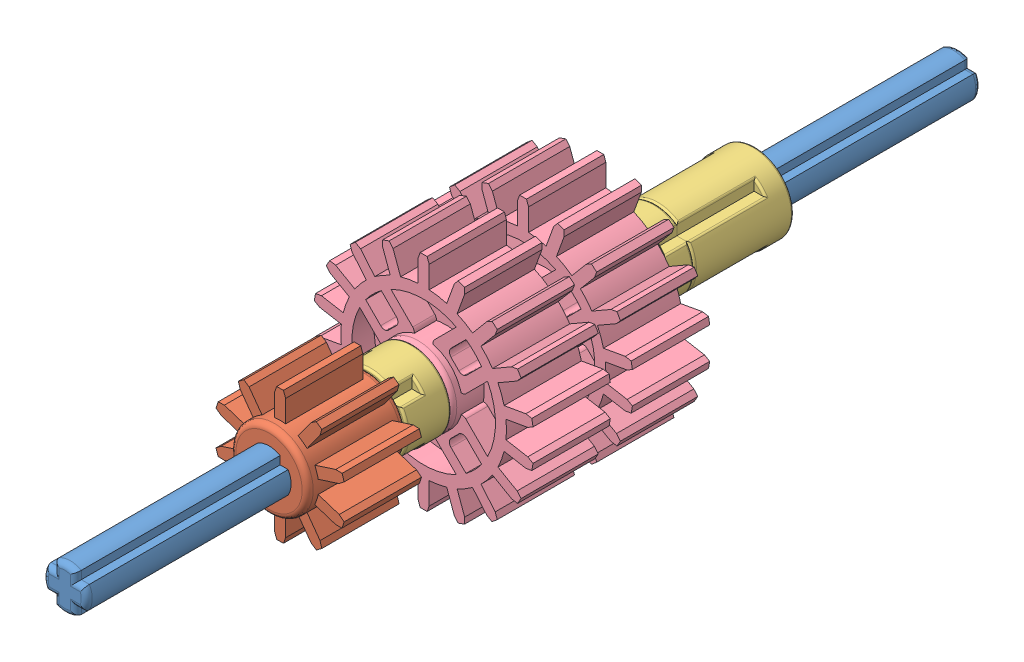
SolidWorks assembly Subconjunto 2º aumento, configuration Default. Lengths in mm.
Overall size (19.8 20 81).
7 component instances, 4 part files, 14 mates.
Components (placement in the parent):
- Veio-1: Veio [Veio 2º aumento] at (-2.8606 1.5336 -17.5324) size (4 4 81)
- Roda Dentada 10-1: Roda Dentada 10 [Default] at (-2.8606 1.5336 40.4676) size (11.6 12 9)
- Freio-1: Freio [Freio Pequeno] at (-2.8606 1.5336 35.9676) x (-1 0 0) z (0 0 -1) size (7 7 4.02)
- Roda Dentada 18-1: Roda Dentada 18 [Default] at (-2.8606 1.5336 27.4676) size (19.8 20 9)
- Roda Dentada 18-2: Roda Dentada 18 [Default] at (-2.8606 1.5336 18.4676) size (19.8 20 9)
- Freio-2: Freio [Freio Pequeno] at (-2.8606 1.5336 9.9676) size (7 7 4.02)
- Freio-4: Freio [Frei Grande] at (-2.8606 1.5336 9.9676) x (-1 0 0) z (0 0 -1) size (7 7 9.02)
Mates (geometry in assembly coordinates):
- Concentric11: concentric aligned: cylinder of Veio-1 through (-2.8606 1.5336 63.4676) axis (0 0 -1) radius 2; cylinder of Roda Dentada 10-1 through (-2.8606 1.5336 44.2851) axis (0 0 -1) radius 2
- Concentric21: concentric anti-aligned: cylinder of Veio-1 through (-2.8606 1.5336 63.4676) axis (0 0 -1) radius 2; cylinder of Freio-1 through (-2.8606 1.5336 31.2851) axis (0 0 1) radius 2
- Concentric31: concentric aligned: cylinder of Veio-1 through (-2.8606 1.5336 63.4676) axis (0 0 -1) radius 2; cylinder of Roda Dentada 18-1 through (-2.8606 1.5336 30.2851) axis (0 0 -1) radius 2
- Concentric41: concentric aligned: cylinder of Veio-1 through (-2.8606 1.5336 63.4676) axis (0 0 -1) radius 2; cylinder of Roda Dentada 18-2 through (-2.8606 1.5336 21.2851) axis (0 0 -1) radius 2
- Concentric61: concentric anti-aligned: cylinder of Veio-1 through (-2.8606 1.5336 63.4676) axis (0 0 -1) radius 2; cylinder of Freio-4 through (-2.8606 1.5336 0.2851) axis (0 0 1) radius 2
- Coincident1: coincident anti-aligned: plane of Veio-1 through (-1.8606 2.5336 63.4676) normal (1 0 0); plane of Freio-4 through (-1.8606 2.5336 0.2851) normal (-1 0 0)
- Concentric7: concentric aligned: cylinder of Veio-1 through (-2.8606 1.5336 63.4676) axis (0 0 -1) radius 2; cylinder of Freio-2 through (-2.8606 1.5336 13.2851) axis (0 0 -1) radius 2
- Coincident2: coincident anti-aligned: plane of Veio-1 through (-1.8606 2.5336 63.4676) normal (1 0 0); plane of Freio-2 through (-1.8606 2.5336 13.2851) normal (-1 0 0)
- Coincident3: coincident anti-aligned: plane of Freio-2 through (-2.8606 1.5336 9.2851) normal (0 0 -1); plane of Freio-4 through (-2.8606 1.5336 9.2851) normal (0 0 1)
- Coincident4: coincident anti-aligned: plane of Roda Dentada 18-2 through (-2.8606 1.5336 13.2851) normal (0 0 -1); plane of Freio-2 through (-2.8606 1.5336 13.2851) normal (0 0 1)
- Coincident5: coincident anti-aligned: plane of Roda Dentada 18-1 through (-2.8606 1.5336 22.2851) normal (0 0 -1); plane of Roda Dentada 18-2 through (-2.8606 1.5336 22.2851) normal (0 0 1)
- Coincident6: coincident anti-aligned: plane of Freio-1 through (-2.8606 1.5336 31.2851) normal (0 0 -1); plane of Roda Dentada 18-1 through (-2.8606 1.5336 31.2851) normal (0 0 1)
- Coincident7: coincident anti-aligned: plane of Roda Dentada 10-1 through (-2.8606 1.5336 35.2851) normal (0 0 -1); plane of Freio-1 through (-2.8606 1.5336 35.2851) normal (0 0 1)
- Width1: width anti-aligned: plane of Veio-1 through (-2.8606 1.5336 -17.5324) normal (0 0 -1); plane of Roda Dentada 10-1 through (-2.8606 1.5336 63.4676) normal (0 0 1); plane of Veio-1 through (-2.8606 1.5336 44.9676) normal (0 0 1); plane of Freio-4 through (-2.8606 1.5336 0.9676) normal (0 0 -1)
